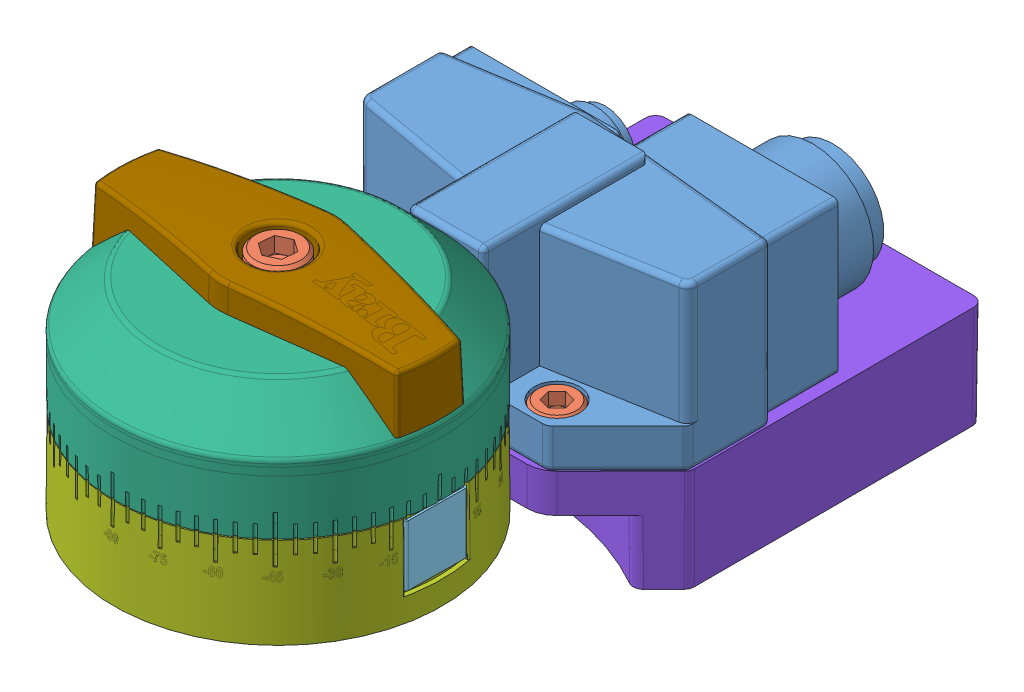
SolidWorks assembly Assem8, configuration Default. Lengths in mm.
Overall size (65.53 72.43 139.73).
13 component instances, 9 part files, 20 mates.
Components (placement in the parent):
- 54-0041-71104-533-1: 54-0041-71104-533 [Default] at (-513.2284 86.1663 -520.1396) size (65.09 33.51 60)
- socket head cap screw_am-1: socket head cap screw_am [B18.3.1M - 5 x 0.8 x 12 Hex SHCS -- 12NHX] at (-528.2535 94.1663 -491.6396) x (0 -1 0) z (-0.706848 0 0.707366) size (17 8.5 8.5)
- 07-5623-72107-1: 07-5623-72107 [Default] at (-528.2295 83.0979 -516.6396) x (0 -1 0) z (0.643698 0 -0.76528) size (25 9.12 9.2)
- socket head cap screw_am-2: socket head cap screw_am [B18.3.1M - 5 x 0.8 x 12 Hex SHCS -- 12NHX] at (-498.2284 94.1663 -491.6396) x (0 -1 0) z (-0.706848 0 -0.707366) size (17 8.5 8.5)
- 54-160A-705P0-1: 54-160A-705P0 [Default] at (-513.2409 115.0207 -451.6122) size (45.64 22.89 45.64)
- 54-000A-73500-1: 54-000A-73500 [Default] at (-512.96 111.412 -483.806) x (-1 -0.000194 0.00096) z (-0.000958 -0.008727 -0.999961) size (12.19 11.94 6.35)
- 54-000A-73500-2: 54-000A-73500 [Default] at (-481.5435 98.8456 -451.2783) x (0.011705 0 -0.999931) z (0.999931 0 0.011705) size (12.19 11.94 6.35)
- 54-000A-92511-1: 54-000A-92511 [Default] at (-513.2409 105.6735 -451.6122) x (-0.999932 0 -0.011665) z (0.011665 0 -0.999932) size (64.76 21.97 66.01)
- 54-000A-92510-1: 54-000A-92510 [Default] at (-513.2409 87.5887 -451.6122) x (0.011705 0 -0.999931) z (0.999931 0 0.011705) size (64.81 35.64 64.77)
- 07-5623-72107-2: 07-5623-72107 [Default] at (-498.2523 83.0979 -516.6396) x (0 -1 0) z (0.643698 0 0.76528) size (25 9.12 9.2)
- socket head cap screw_am-3: socket head cap screw_am [B18.3.1M - 6 x 1.0 x 30 Hex SHCS -- 30NHX] at (-513.2409 132.7047 -451.6122) x (0 -1 0) z (-0.995947 0 -0.089939) size (36 10 10)
- 54-160A-705S0-1: 54-160A-705S0 [Default] at (-513.2925 86.1663 -558.5542) x (-1 0 0.000958) z (-0.000958 0 -1) size (64.77 20.58 72.89)
- 54-000A-92512-1: 54-000A-92512 [Default] at (-513.2409 121.3707 -451.6122) x (-0.998952 0 -0.045767) z (0.045767 0 -0.998952) size (64.52 13.44 23.07)
Mates (geometry in assembly coordinates):
- Coincident1: coincident: plane of 54-160A-705P0-1 through (-513.2409 115.0207 -451.6122) normal (0 1 0); plane of 54-000A-92510-1 through (-512.9897 115.0207 -473.0738) normal (0 -1 0)
- Coincident2: coincident: plane of 54-000A-73500-2 through (-482.742 104.8146 -457.3888) normal (-0.999931 0 -0.011705); plane of 54-000A-92510-1 through (-482.8138 87.5887 -451.2561) normal (0.999931 0 0.011705)
- Coincident3: coincident: plane of 54-000A-92511-1 through (-513.3877 118.1957 -439.0274) normal (0 -1 0); plane of 54-000A-92510-1 through (-513.0908 118.1957 -464.4384) normal (0 1 0)
- Parallel1: parallel: line of 54-000A-73500-2 through (-482.1482 92.8766 -445.189) axis (0 1 0); plane of 54-000A-92510-1 through (-482.8859 87.5887 -445.097) normal (0.046595 0 -0.998914)
- Coincident4: coincident: plane of 54-000A-92511-1 through (-513.358 121.3707 -441.5799) normal (0 1 0); plane of 54-000A-92512-1 through (-513.5798 121.3707 -444.2159) normal (0 -1 0)
- Coincident5: coincident: plane of socket head cap screw_am-3 through (-513.6906 126.7047 -446.6325) normal (0 -1 0); plane of 54-000A-92512-1 through (-513.4926 126.7047 -446.118) normal (0 1 0)
- Parallel2: parallel: plane of 54-000A-73500-1 through (-506.8652 117.382 -483.864) normal (-0.000958 -0.008727 -0.999961); plane of 54-160A-705S0-1 through (-480.9075 86.1663 -558.5852) normal (-0.000958 -0.008727 -0.999961)
- Coincident6: coincident: plane of 54-0041-71104-533-1 through (-513.2284 86.1663 -520.1396) normal (0 -1 0); plane of 54-160A-705S0-1 through (-498.2284 86.1663 -491.6396) normal (0 1 0)
- Coincident7: coincident: line of 54-000A-73500-1 through (-519.0552 113.6464 -482.5496) axis (-0.000203 0.999962 -0.008726); plane of 54-000A-92511-1 through (-519.0451 105.6735 -482.1112) normal (0.99973 0 -0.023239)
- Coincident8: coincident: plane of 54-0041-71104-533-1 through (-498.2284 89.1663 -491.6396) normal (0 1 0); plane of socket head cap screw_am-2 through (-501.2347 89.1663 -488.6355) normal (0 -1 0)
- Concentric1: concentric: circle of 07-5623-72107-2; circle of 54-160A-705S0-1
- Concentric2: concentric: cone of 07-5623-72107-2 through (-498.2523 85.3479 -516.6396) axis (0 -1 0); cone of 54-160A-705S0-1 through (-498.2523 86.1663 -516.6396) axis (0 -1 0)
- Concentric3: concentric: cylinder of 54-0041-71104-533-1 through (-498.2284 82.2488 -491.6396) axis (0 1 0) radius 4.5; cylinder of socket head cap screw_am-2 through (-498.2284 125.9163 -491.6396) axis (0 1 0) radius 4.25
- Concentric4: concentric: cylinder of 07-5623-72107-2 through (-498.2523 82.2979 -516.6396) axis (0 -1 0) radius 2.5; cylinder of 54-160A-705S0-1 through (-498.2523 86.1663 -516.6396) axis (0 1 0) radius 2.8067
- Concentric5: concentric: cylinder of 54-160A-705P0-1 through (-513.2409 124.3545 -451.6122) axis (0 -1 0) radius 3.3; cylinder of 54-000A-92510-1 through (-513.2409 78.2549 -451.6122) axis (0 1 0) radius 3.3
- Concentric6: concentric: cylinder of 54-000A-92511-1 through (-513.2409 108.8619 -451.6122) axis (0 1 0) radius 3.3; cylinder of 54-000A-92510-1 through (-513.2409 78.2549 -451.6122) axis (0 1 0) radius 3.3
- Concentric7: concentric: cylinder of 54-000A-92511-1 through (-513.2409 108.8619 -451.6122) axis (0 1 0) radius 3.3; cylinder of socket head cap screw_am-3 through (-513.2409 164.4547 -451.6122) axis (0 1 0) radius 3
- Concentric8: concentric: cylinder of 54-000A-92511-1 through (-513.2409 108.8619 -451.6122) axis (0 1 0) radius 3.3; cylinder of 54-000A-92512-1 through (-513.2409 121.3707 -451.6122) axis (0 -1 0) radius 3.3
- Concentric9: concentric: circle of 07-5623-72107-2; circle of 54-160A-705S0-1
- Concentric10: concentric: cylinder of 54-0041-71104-533-1 through (-498.2284 82.2488 -491.6396) axis (0 1 0) radius 4.5; circle of 54-160A-705S0-1
